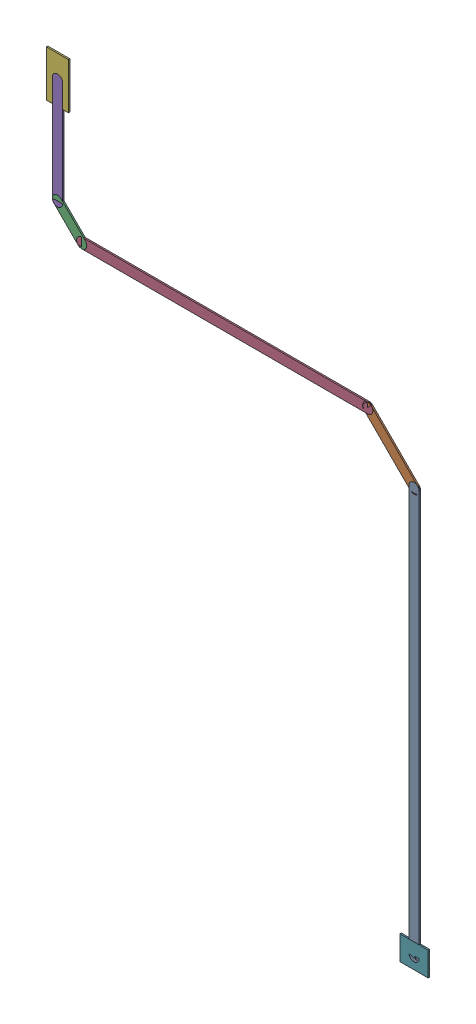
SolidWorks assembly NetIC2_12, configuration Predeterminado. Lengths in mm.
Overall size (9.48 15.28 0.04).
21 component instances, 7 part files, 0 mates.
Components (placement in the parent):
- Track (31.05mm,41.5mm)(31.05mm,51.55mm) on Top Layer-1: Track (31.05mm,41.5mm)(31.05mm,51.55mm) on Top Layer [Predeterminado] at origin size (0.25 10.3 0.04)
  - Track (31.05mm,41.5mm)(31.05mm,51.55mm) on Top Layer-1-1: Track (31.05mm,41.5mm)(31.05mm,51.55mm) on Top Layer-1 [Predeterminado] at (-68.317 -44.187 -0.0457) size (0.25 10.3 0.04)
    - Track (31.05mm,41.5mm)(31.05mm,51.55mm) on Top Layer-Part-1-1: Track (31.05mm,41.5mm)(31.05mm,51.55mm) on Top Layer-Part-1 [Predeterminado] at origin size (0.25 10.3 0.04)
- Track (29.9mm,52.7mm)(31.05mm,51.55mm) on Top Layer-1: Track (29.9mm,52.7mm)(31.05mm,51.55mm) on Top Layer [Predeterminado] at origin size (1.4 1.4 0.04)
  - Track (29.9mm,52.7mm)(31.05mm,51.55mm) on Top Layer-1-1: Track (29.9mm,52.7mm)(31.05mm,51.55mm) on Top Layer-1 [Predeterminado] at (-68.317 -44.187 -0.0457) size (1.4 1.4 0.04)
    - Track (29.9mm,52.7mm)(31.05mm,51.55mm) on Top Layer-Part-1-1: Track (29.9mm,52.7mm)(31.05mm,51.55mm) on Top Layer-Part-1 [Predeterminado] at origin size (1.4 1.4 0.04)
- Track (22.2mm,53.3mm)(22.8mm,52.7mm) on Top Layer-1: Track (22.2mm,53.3mm)(22.8mm,52.7mm) on Top Layer [Predeterminado] at origin size (0.85 0.85 0.04)
  - Track (22.2mm,53.3mm)(22.8mm,52.7mm) on Top Layer-1-1: Track (22.2mm,53.3mm)(22.8mm,52.7mm) on Top Layer-1 [Predeterminado] at (-68.317 -44.187 -0.0457) size (0.85 0.85 0.04)
    - Track (22.2mm,53.3mm)(22.8mm,52.7mm) on Top Layer-Part-1-1: Track (22.2mm,53.3mm)(22.8mm,52.7mm) on Top Layer-Part-1 [Predeterminado] at origin size (0.85 0.85 0.04)
- Track (22.8mm,52.7mm)(29.9mm,52.7mm) on Top Layer-1: Track (22.8mm,52.7mm)(29.9mm,52.7mm) on Top Layer [Predeterminado] at origin size (7.35 0.25 0.04)
  - Track (22.8mm,52.7mm)(29.9mm,52.7mm) on Top Layer-1-1: Track (22.8mm,52.7mm)(29.9mm,52.7mm) on Top Layer-1 [Predeterminado] at (-68.317 -44.187 -0.0457) size (7.35 0.25 0.04)
    - Track (22.8mm,52.7mm)(29.9mm,52.7mm) on Top Layer-Part-1-1: Track (22.8mm,52.7mm)(29.9mm,52.7mm) on Top Layer-Part-1 [Predeterminado] at origin size (7.35 0.25 0.04)
- Track (22.2mm,53.3mm)(22.2mm,55.903mm) on Top Layer-1: Track (22.2mm,53.3mm)(22.2mm,55.903mm) on Top Layer [Predeterminado] at origin size (0.25 2.86 0.04)
  - Track (22.2mm,53.3mm)(22.2mm,55.903mm) on Top Layer-1-1: Track (22.2mm,53.3mm)(22.2mm,55.903mm) on Top Layer-1 [Predeterminado] at (-68.317 -44.187 -0.0457) size (0.25 2.86 0.04)
    - Track (22.2mm,53.3mm)(22.2mm,55.903mm) on Top Layer-Part-1-1: Track (22.2mm,53.3mm)(22.2mm,55.903mm) on Top Layer-Part-1 [Predeterminado] at origin size (0.25 2.86 0.04)
- Pad ADXL345-12(22.2mm,55.903mm) on Top Layer-1: Pad ADXL345-12(22.2mm,55.903mm) on Top Layer [Predeterminado] at origin size (0.55 1.15 0.04)
  - Pad ADXL345-12(22.2mm,55.903mm) on Top Layer-1-1: Pad ADXL345-12(22.2mm,55.903mm) on Top Layer-1 [Predeterminado] at (-68.317 -44.187 -0.0457) size (0.55 1.15 0.04)
    - Pad ADXL345-12(22.2mm,55.903mm) on Top Layer-Part-1-1: Pad ADXL345-12(22.2mm,55.903mm) on Top Layer-Part-1 [Predeterminado] at origin size (0.55 1.15 0.04)
- Pad R3-2(31.05mm,41.5mm) on Top Layer-1: Pad R3-2(31.05mm,41.5mm) on Top Layer [Predeterminado] at origin size (0.7 0.6 0.04)
  - Pad R3-2(31.05mm,41.5mm) on Top Layer-1-1: Pad R3-2(31.05mm,41.5mm) on Top Layer-1 [Predeterminado] at (-68.317 -44.187 -0.0457) size (0.7 0.6 0.04)
    - Pad R3-2(31.05mm,41.5mm) on Top Layer-Part-1-1: Pad R3-2(31.05mm,41.5mm) on Top Layer-Part-1 [Predeterminado] at origin size (0.7 0.6 0.04)
